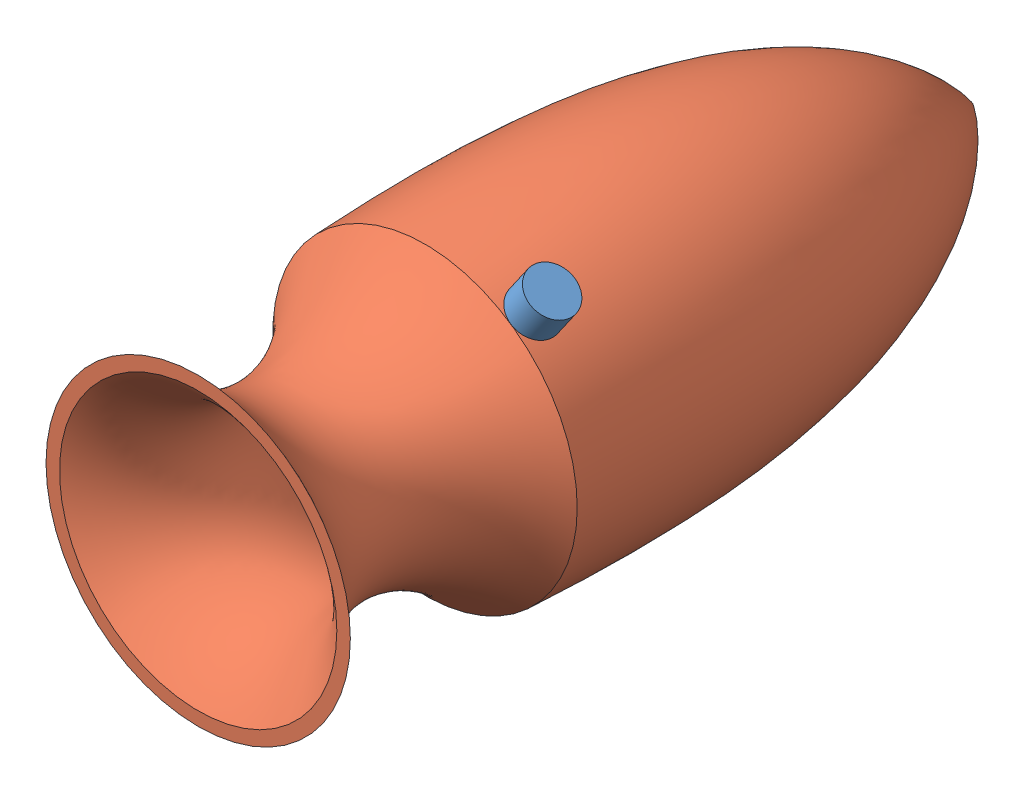
SolidWorks assembly rocket body final, configuration Default. Lengths in mm.
Overall size (2076.69 2101.98 5000).
2 component instances, 2 part files, 2 mates.
Components (placement in the parent):
- rocket part-1: rocket part [Default] at (864.0757 1233.5365 -591.098) x (-0.002316 0.049877 0.998753) z (0.826569 -0.562036 0.029984) size (300 200 300)
- Xdesign rocket body-1: Xdesign rocket body [Default] at (201.5517 261.6908 27.8048) size (2076.69 2076.69 5000)
Mates (geometry in assembly coordinates):
- Tangent5: tangent: plane of rocket part-1 through (751.5095 1068.4151 -583.1129) normal (-0.562831 -0.825607 0.039925); face of Xdesign rocket body-1
- Tangent7: tangent: circle of rocket part-1; circle of Xdesign rocket body-1
